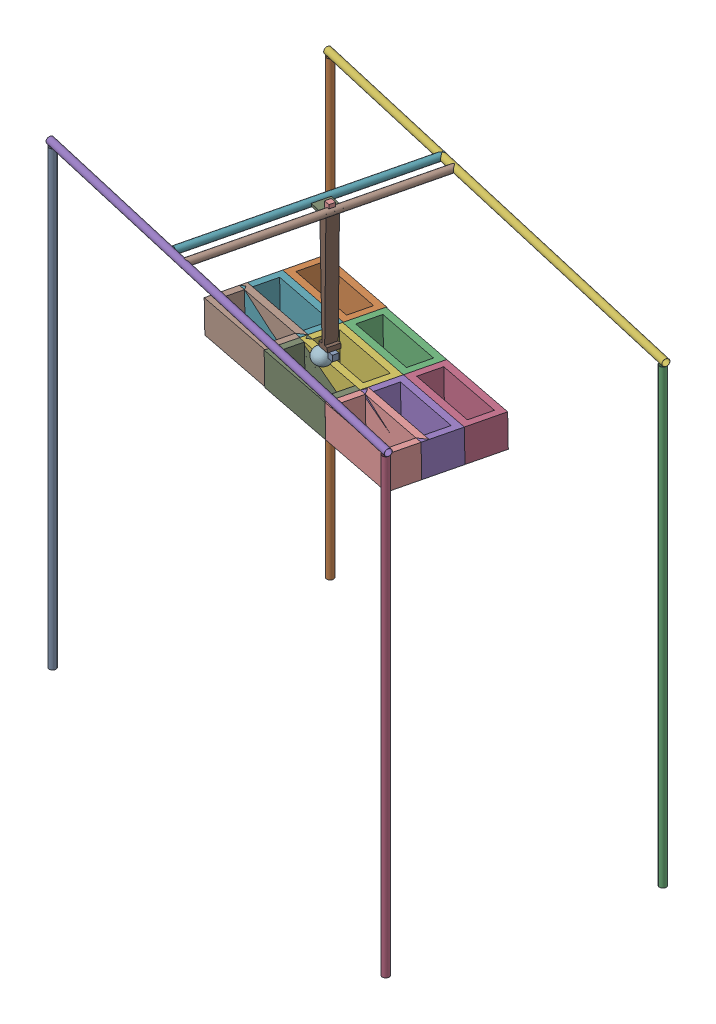
SolidWorks assembly Assem3, configuration Default. Lengths in mm.
Overall size (2218.63 2049.89 1457.96).
22 component instances, 7 part files, 85 mates.
Components (placement in the parent):
- Post-1: Post [Default] at (-708.0978 -578.8244 766.8983) size (30 2000 30)
- Post-2: Post [Default] at (-447.6841 -587.9996 -202.6406) x (-0.685433 0 0.728135) z (-0.728135 0 -0.685433) size (30 2000 30)
- Post-3: Post [Default] at (1471.9629 -588.1508 242.4272) x (0.918656 0 0.395059) z (-0.395059 0 0.918656) size (30 2000 30)
- Post-4: Post [Default] at (1211.4126 -579.3895 1210.0463) x (-0.750465 0 0.660911) z (-0.660911 0 -0.750465) size (30 2000 30)
- Post-5: Post [Default] at (1226.0281 1435.6105 1213.4205) x (-0.214051 -0.307477 0.927168) z (0.069166 -0.951555 -0.299597) size (30 2000 30)
- Post-6: Post [Default] at (1486.9923 1426.4353 244.0087) x (-0.187597 -0.551833 0.812581) z (0.124134 -0.833955 -0.53769) size (30 2000 30)
- CrossBar-1: CrossBar [Default] at (199.2269 1426.3635 -61.3498) x (-0.865673 -0.460846 -0.195528) z (-0.224939 0.009145 0.97433) size (30 30 1000)
- CrossBar-2: CrossBar [Default] at (270.8033 1426.4246 -37.975) x (-0.397766 -0.913702 -0.083254) z (-0.224939 0.009145 0.97433) size (30 30 1000)
- PneumaticBase-1: PneumaticBase [Default] at (100.0341 1426.9597 429.3848) x (0.974371 0 0.224948) z (-0.224939 0.009145 0.97433) size (75 10 75)
- MotorPlaceHolder-1: MotorPlaceHolder [Default] at (144.8147 1436.7365 414.62) x (0.974371 0 0.224948) z (-0.224939 0.009145 0.97433) size (25 25 25)
- PneumaticPlaceHolder-1: PneumaticPlaceHolder [Default] at (173.7901 1021.101 385.5573) x (-0.97362 -0.041413 -0.224386) z (-0.224939 0.009145 0.97433) size (55.74 520 50)
- Scoop-1: Scoop [Default] at (142.921 869.2738 425.0805) x (0.404961 0.888332 0.216502) z (-0.913665 0.402216 0.058646) size (37.5 75 75)
- MotorPlaceHolder-2: MotorPlaceHolder [Default] at (179.0904 883.31 432.6726) x (0.97362 0.041413 0.224386) z (-0.224939 0.009145 0.97433) size (25 25 25)
- Box-1: Box [Default] at (-335.0347 663.8183 117.5582) x (0.97362 0.041413 0.224386) z (-0.224939 0.009145 0.97433) size (360 140 160)
- Box-2: Box [Default] at (14.6565 679.6608 201.6882) x (0.97362 0.041413 0.224386) z (-0.224939 0.009145 0.97433) size (360 140 160)
- Box-3: Box [Default] at (365.1729 694.569 282.41) x (0.97362 0.041413 0.224386) z (-0.224939 0.009145 0.97433) size (360 140 160)
- Box-4: Box [Default] at (329.1827 696.0322 438.3028) x (0.97362 0.041413 0.224386) z (-0.224939 0.009145 0.97433) size (360 140 160)
- Box-5: Box [Default] at (-21.3337 681.124 357.581) x (0.97362 0.041413 0.224386) z (-0.224939 0.009145 0.97433) size (360 140 160)
- Box-6: Box [Default] at (-371.0249 665.2815 273.451) x (0.97362 0.041413 0.224386) z (-0.224939 0.009145 0.97433) size (360 140 160)
- Box-7: Box [Default] at (-400.2669 666.4703 400.1139) x (0.97362 0.041413 0.224386) z (-0.224939 0.009145 0.97433) size (360 140 160)
- Box-8: Box [Default] at (-50.5757 682.3128 484.2439) x (0.97362 0.041413 0.224386) z (-0.224939 0.009145 0.97433) size (360 140 160)
- Box-9: Box [Default] at (299.9407 697.221 564.9657) x (0.97362 0.041413 0.224386) z (-0.224939 0.009145 0.97433) size (360 140 160)
Mates (geometry in assembly coordinates):
- Parallel1: parallel aligned: cylinder of Post-5 through (-722.7133 1435.6105 763.5241) axis (0.974371 0 0.224948) radius 15; cylinder of Post-6 through (-461.7491 1426.4353 -205.8877) axis (0.974371 0 0.224948) radius 15
- Parallel2: parallel aligned: cylinder of Post-1 through (-708.0978 1421.1756 766.8983) axis (0 -1 0) radius 15; cylinder of Post-2 through (-447.6841 1412.0004 -202.6406) axis (0 -1 0) radius 15
- Parallel3: parallel aligned: cylinder of Post-3 through (1471.9629 1411.8492 242.4272) axis (0 -1 0) radius 15; cylinder of Post-4 through (1211.4126 1420.6105 1210.0463) axis (0 -1 0) radius 15
- Parallel4: parallel aligned: cylinder of Post-1 through (-708.0978 1421.1756 766.8983) axis (0 -1 0) radius 15; cylinder of Post-4 through (1211.4126 1420.6105 1210.0463) axis (0 -1 0) radius 15
- Parallel5: parallel aligned: cylinder of Post-3 through (1471.9629 1411.8492 242.4272) axis (0 -1 0) radius 15; cylinder of Post-4 through (1211.4126 1420.6105 1210.0463) axis (0 -1 0) radius 15
- Parallel6: parallel aligned: cylinder of Post-2 through (-447.6841 1412.0004 -202.6406) axis (0 -1 0) radius 15; cylinder of Post-3 through (1471.9629 1411.8492 242.4272) axis (0 -1 0) radius 15
- Perpendicular1: perpendicular: cylinder of Post-2 through (-447.6841 1412.0004 -202.6406) axis (0 -1 0) radius 15; cylinder of Post-6 through (-461.7491 1426.4353 -205.8877) axis (0.974371 0 0.224948) radius 15
- Perpendicular2: perpendicular: cylinder of Post-2 through (-447.6841 1412.0004 -202.6406) axis (0 -1 0) radius 15; cylinder of Post-5 through (-722.7133 1435.6105 763.5241) axis (0.974371 0 0.224948) radius 15
- Perpendicular8: perpendicular: cylinder of Post-4 through (1211.4126 1420.6105 1210.0463) axis (0 -1 0) radius 15; cylinder of Post-5 through (-722.7133 1435.6105 763.5241) axis (0.974371 0 0.224948) radius 15
- Perpendicular9: perpendicular: cylinder of Post-1 through (-708.0978 1421.1756 766.8983) axis (0 -1 0) radius 15; cylinder of Post-5 through (-722.7133 1435.6105 763.5241) axis (0.974371 0 0.224948) radius 15
- Perpendicular10: perpendicular: cylinder of Post-3 through (1471.9629 1411.8492 242.4272) axis (0 -1 0) radius 15; cylinder of Post-6 through (-461.7491 1426.4353 -205.8877) axis (0.974371 0 0.224948) radius 15
- Perpendicular11: perpendicular: cylinder of Post-2 through (-447.6841 1412.0004 -202.6406) axis (0 -1 0) radius 15; cylinder of Post-6 through (-461.7491 1426.4353 -205.8877) axis (0.974371 0 0.224948) radius 15
- Perpendicular17: perpendicular: cylinder of Post-1 through (-708.0978 1421.1756 766.8983) axis (0 -1 0) radius 15; cylinder of Post-5 through (-722.7133 1435.6105 763.5241) axis (0.974371 0 0.224948) radius 15
- Perpendicular18: perpendicular: cylinder of Post-4 through (1211.4126 1420.6105 1210.0463) axis (0 -1 0) radius 15; cylinder of Post-5 through (-722.7133 1435.6105 763.5241) axis (0.974371 0 0.224948) radius 15
- Tangent23: tangent: circle of Post-1; circle of Post-5
- Tangent24: tangent: circle of Post-4; circle of Post-5
- Tangent29: tangent: circle of Post-2; circle of Post-6
- Tangent32: tangent: plane of Post-3; plane of Post-6 through (1486.9923 1426.4353 244.0087) normal (0.974371 0 0.224948)
- Lock1: lock: unknown of Post-3; unknown of Post-6
- Lock2: lock: unknown of Post-2; unknown of Post-6
- Lock3: lock: unknown of Post-1; unknown of Post-5
- Lock4: lock: unknown of Post-4; unknown of Post-5
- Perpendicular21: perpendicular: cylinder of Post-5 through (-722.7133 1435.6105 763.5241) axis (0.974371 0 0.224948) radius 15; cylinder of CrossBar-1 through (-25.7119 1435.5085 912.9802) axis (0.224939 -0.009145 -0.97433) radius 15
- Tangent38: tangent aligned: cylinder of Post-6 through (-461.7491 1426.4353 -205.8877) axis (0.974371 0 0.224948) radius 15; cylinder of CrossBar-1 through (-25.7119 1435.5085 912.9802) axis (0.224939 -0.009145 -0.97433) radius 15
- Tangent40: tangent aligned: cylinder of Post-5 through (-722.7133 1435.6105 763.5241) axis (0.974371 0 0.224948) radius 15; cylinder of CrossBar-2 through (45.8645 1435.5695 936.355) axis (0.224939 -0.009145 -0.97433) radius 15
- Distance4: distance = 75 mm: cylinder of CrossBar-1 through (-25.7119 1435.5085 912.9802) axis (0.224939 -0.009145 -0.97433) radius 15; cylinder of CrossBar-2 through (45.8645 1435.5695 936.355) axis (0.224939 -0.009145 -0.97433) radius 15
- Lock7: lock: unknown of Post-3; unknown of Post-4
- Lock8: lock: unknown of Post-1; unknown of Post-2
- Coincident14: coincident: cylinder of CrossBar-2 through (45.8645 1435.5695 936.355) axis (0.224939 -0.009145 -0.97433) radius 15; line of PneumaticBase-1 through (173.1324 1436.9593 446.1668) axis (0.224939 -0.009145 -0.97433)
- Coincident16: coincident: cylinder of CrossBar-1 through (-25.7119 1435.5085 912.9802) axis (0.224939 -0.009145 -0.97433) radius 15; line of PneumaticBase-1 through (116.925 1436.2734 356.2209) axis (-0.224939 0.009145 0.97433)
- Parallel23: parallel aligned: cylinder of Post-5 through (-722.7133 1435.6105 763.5241) axis (0.974371 0 0.224948) radius 15; line of PneumaticBase-1 through (100.0546 1436.9593 429.2957) axis (0.974371 0 0.224948)
- Parallel24: parallel anti-aligned: cylinder of Post-6 through (-461.7491 1426.4353 -205.8877) axis (0.974371 0 0.224948) radius 15; line of PneumaticBase-1 through (190.0028 1436.2734 373.0921) axis (-0.974371 0 -0.224948)
- Tangent47: tangent: cylinder of CrossBar-1 through (-25.7119 1435.5085 912.9802) axis (0.224939 -0.009145 -0.97433) radius 15; line of PneumaticBase-1 through (116.925 1436.2734 356.2209) axis (-0.224939 0.009145 0.97433)
- Tangent48: tangent: cylinder of CrossBar-2 through (45.8645 1435.5695 936.355) axis (0.224939 -0.009145 -0.97433) radius 15; line of PneumaticBase-1 through (173.1324 1436.9593 446.1668) axis (0.224939 -0.009145 -0.97433)
- Coincident24: coincident anti-aligned: plane of PneumaticBase-1 through (100.0546 1436.9593 429.2957) normal (0.002057 0.999958 -0.008911); plane of MotorPlaceHolder-1 through (144.8147 1436.7365 414.62) normal (-0.002057 -0.999958 0.008911)
- Parallel25: parallel aligned: plane of PneumaticBase-1 through (116.925 1436.2734 356.2209) normal (0.224939 -0.009145 -0.97433); plane of MotorPlaceHolder-1 through (150.4896 1461.5068 390.039) normal (0.224939 -0.009145 -0.97433)
- Lock10: lock: unknown of PneumaticBase-1; unknown of MotorPlaceHolder-1
- Coincident27: coincident anti-aligned: plane of PneumaticBase-1 through (100.0341 1426.9597 429.3848) normal (-0.002057 -0.999958 0.008911); plane of PneumaticPlaceHolder-1 through (163.3769 1426.8408 430.6623) normal (0.002057 0.999958 -0.008911)
- Parallel27: parallel aligned: plane of PneumaticBase-1 through (100.0546 1436.9593 429.2957) normal (-0.224939 0.009145 0.97433); plane of PneumaticPlaceHolder-1 through (162.5431 1021.5583 434.2738) normal (-0.224939 0.009145 0.97433)
- Parallel28: parallel anti-aligned: plane of MotorPlaceHolder-1 through (144.8661 1461.7354 414.3972) normal (-0.974371 0 -0.224948); plane of PneumaticPlaceHolder-1 through (167.0907 1021.5583 435.3237) normal (0.974371 0 0.224948)
- Lock11: lock: unknown of PneumaticBase-1; unknown of PneumaticPlaceHolder-1
- Coincident33: coincident anti-aligned: plane of PneumaticPlaceHolder-1 through (166.8987 907.9322 436.3458) normal (0.038298 -0.9991 0.018219); plane of MotorPlaceHolder-2 through (178.1329 908.2875 432.2171) normal (-0.038298 0.9991 -0.018219)
- Parallel31: parallel aligned: plane of PneumaticPlaceHolder-1 through (162.5431 1021.5583 434.2738) normal (-0.224939 0.009145 0.97433); plane of MotorPlaceHolder-2 through (178.1329 908.2875 432.2171) normal (-0.224939 0.009145 0.97433)
- Parallel32: parallel aligned: plane of PneumaticPlaceHolder-1 through (129.1518 1020.1379 426.5782) normal (-0.97362 -0.041413 -0.224386); plane of MotorPlaceHolder-2 through (178.1329 908.2875 432.2171) normal (-0.97362 -0.041413 -0.224386)
- Tangent51: tangent anti-aligned: sphere of Scoop-1; plane of MotorPlaceHolder-2 through (178.1329 908.2875 432.2171) normal (-0.97362 -0.041413 -0.224386)
- Lock12: lock: unknown of PneumaticPlaceHolder-1; unknown of MotorPlaceHolder-2
- Tangent52: tangent anti-aligned: plane of PneumaticPlaceHolder-1 through (166.8987 907.9322 436.3458) normal (0.038298 -0.9991 0.018219); sphere of Scoop-1
- Tangent53: tangent anti-aligned: sphere of Scoop-1; plane of MotorPlaceHolder-2 through (178.1329 908.2875 432.2171) normal (-0.97362 -0.041413 -0.224386)
- Coincident34: coincident anti-aligned: plane of Box-1 through (10.1068 818.6011 195.7866) normal (0.97362 0.041413 0.224386); plane of Box-2 through (9.2948 819.5348 199.1375) normal (-0.97362 -0.041413 -0.224386)
- Coincident35: coincident anti-aligned: plane of Box-2 through (359.798 834.4436 279.9165) normal (0.97362 0.041413 0.224386); plane of Box-3 through (359.8112 834.443 279.8593) normal (-0.97362 -0.041413 -0.224386)
- Parallel33: parallel aligned: plane of Box-2 through (9.2948 819.5348 199.1375) normal (-0.224939 0.009145 0.97433); plane of Box-3 through (359.8112 834.443 279.8593) normal (-0.224939 0.009145 0.97433)
- Parallel34: parallel aligned: plane of Box-1 through (-340.3964 803.6923 115.0075) normal (-0.224939 0.009145 0.97433); plane of Box-2 through (9.2948 819.5348 199.1375) normal (-0.224939 0.009145 0.97433)
- Parallel35: parallel aligned: plane of Box-2 through (45.285 818.0716 43.2447) normal (0.224939 -0.009145 -0.97433); plane of Box-3 through (395.8014 832.9798 123.9665) normal (0.224939 -0.009145 -0.97433)
- Parallel36: parallel aligned: plane of Box-1 through (-304.4062 802.2291 -40.8853) normal (0.224939 -0.009145 -0.97433); plane of Box-2 through (45.285 818.0716 43.2447) normal (0.224939 -0.009145 -0.97433)
- Parallel37: parallel aligned: plane of Box-1 through (-335.0347 663.8183 117.5582) normal (0.038298 -0.9991 0.018219); plane of Box-2 through (14.6565 679.6608 201.6882) normal (0.038298 -0.9991 0.018219)
- Coincident41: coincident aligned: plane of Box-2 through (14.6565 679.6608 201.6882) normal (0.038298 -0.9991 0.018219); plane of Box-3 through (365.1729 694.569 282.41) normal (0.038298 -0.9991 0.018219)
- Lock13: lock: unknown of Box-1; unknown of Box-2
- Lock14: lock: unknown of Box-2; unknown of Box-3
- Parallel38: parallel aligned: plane of PneumaticPlaceHolder-1 through (147.8851 1020.9348 430.8956) normal (-0.97362 -0.041413 -0.224386); plane of Box-1 through (-340.3964 803.6923 115.0075) normal (-0.97362 -0.041413 -0.224386)
- Parallel39: parallel aligned: plane of MotorPlaceHolder-1 through (144.8661 1461.7354 414.3972) normal (-0.224939 0.009145 0.97433); plane of Box-2 through (9.2948 819.5348 199.1375) normal (-0.224939 0.009145 0.97433)
- Parallel40: parallel aligned: plane of MotorPlaceHolder-2 through (202.4734 909.3228 437.8267) normal (0.97362 0.041413 0.224386); plane of Box-3 through (710.3144 849.3518 360.6383) normal (0.97362 0.041413 0.224386)
- Coincident47: coincident aligned: plane of Box-4 through (329.1827 696.0322 438.3028) normal (0.038298 -0.9991 0.018219); plane of Box-5 through (-21.3337 681.124 357.581) normal (0.038298 -0.9991 0.018219)
- Parallel41: parallel aligned: plane of Box-5 through (-21.3337 681.124 357.581) normal (0.038298 -0.9991 0.018219); plane of Box-6 through (-371.0249 665.2815 273.451) normal (0.038298 -0.9991 0.018219)
- Lock15: lock: unknown of Box-5; unknown of Box-6
- Lock16: lock: unknown of Box-4; unknown of Box-5
- Parallel42: parallel aligned: plane of Box-5 through (-26.6954 820.998 355.0303) normal (-0.224939 0.009145 0.97433); plane of Box-6 through (-376.3866 805.1555 270.9003) normal (-0.224939 0.009145 0.97433)
- Coincident48: coincident anti-aligned: plane of Box-5 through (-26.6954 820.998 355.0303) normal (-0.97362 -0.041413 -0.224386); plane of Box-6 through (-25.8834 820.0643 351.6793) normal (0.97362 0.041413 0.224386)
- Parallel43: parallel aligned: plane of Box-4 through (359.8112 834.443 279.8593) normal (0.224939 -0.009145 -0.97433); plane of Box-5 through (9.2948 819.5348 199.1375) normal (0.224939 -0.009145 -0.97433)
- Parallel44: parallel aligned: plane of Box-5 through (9.2948 819.5348 199.1375) normal (0.224939 -0.009145 -0.97433); plane of Box-6 through (-340.3964 803.6923 115.0075) normal (0.224939 -0.009145 -0.97433)
- Parallel45: parallel aligned: plane of Box-4 through (323.821 835.9062 435.7521) normal (-0.224939 0.009145 0.97433); plane of Box-5 through (-26.6954 820.998 355.0303) normal (-0.224939 0.009145 0.97433)
- Coincident49: coincident anti-aligned: plane of Box-4 through (323.821 835.9062 435.7521) normal (-0.97362 -0.041413 -0.224386); plane of Box-5 through (323.8078 835.9068 435.8093) normal (0.97362 0.041413 0.224386)
- Coincident51: coincident anti-aligned: line of Box-2 through (9.2948 819.5348 199.1375) axis (0.97362 0.041413 0.224386); line of Box-5 through (359.798 834.4436 279.9165) axis (-0.97362 -0.041413 -0.224386)
- Coincident52: coincident aligned: line of Box-3 through (710.3144 849.3518 360.6383) axis (0.224939 -0.009145 -0.97433); line of Box-4 through (674.3242 850.815 516.5311) axis (0.224939 -0.009145 -0.97433)
- Parallel46: parallel aligned: plane of Box-7 through (-400.2669 666.4703 400.1139) normal (0.038298 -0.9991 0.018219); plane of Box-8 through (-50.5757 682.3128 484.2439) normal (0.038298 -0.9991 0.018219)
- Coincident53: coincident anti-aligned: plane of Box-7 through (-55.1255 821.2531 478.3422) normal (0.97362 0.041413 0.224386); plane of Box-8 through (-55.9375 822.1869 481.6932) normal (-0.97362 -0.041413 -0.224386)
- Parallel47: parallel aligned: plane of Box-8 through (-19.9473 820.7237 325.8004) normal (0.224939 -0.009145 -0.97433); plane of Box-9 through (330.5691 835.6319 406.5222) normal (0.224939 -0.009145 -0.97433)
- Parallel48: parallel aligned: plane of Box-7 through (-405.6286 806.3444 397.5632) normal (-0.224939 0.009145 0.97433); plane of Box-8 through (-55.9375 822.1869 481.6932) normal (-0.224939 0.009145 0.97433)
- Lock17: lock: unknown of Box-7; unknown of Box-8
- Lock18: lock: unknown of Box-8; unknown of Box-9
- Parallel49: parallel aligned: plane of Box-8 through (-55.9375 822.1869 481.6932) normal (-0.224939 0.009145 0.97433); plane of Box-9 through (294.5789 837.0951 562.415) normal (-0.224939 0.009145 0.97433)
- Coincident54: coincident anti-aligned: plane of Box-8 through (294.5657 837.0956 562.4722) normal (0.97362 0.041413 0.224386); plane of Box-9 through (294.5789 837.0951 562.415) normal (-0.97362 -0.041413 -0.224386)
- Parallel50: parallel aligned: plane of Box-7 through (-369.6384 804.8812 241.6704) normal (0.224939 -0.009145 -0.97433); plane of Box-8 through (-19.9473 820.7237 325.8004) normal (0.224939 -0.009145 -0.97433)
- Coincident55: coincident aligned: plane of Box-8 through (-50.5757 682.3128 484.2439) normal (0.038298 -0.9991 0.018219); plane of Box-9 through (299.9407 697.221 564.9657) normal (0.038298 -0.9991 0.018219)
- Coincident56: coincident: line of Box-4 through (674.3242 850.815 516.5311) axis (0.224939 -0.009145 -0.97433); plane of Box-9 through (645.0821 852.0038 643.194) normal (0.97362 0.041413 0.224386)
- Coincident57: coincident anti-aligned: line of Box-5 through (9.2613 821.9661 332.532) axis (0.97362 0.041413 0.224386); line of Box-8 through (330.5559 835.6324 406.5794) axis (-0.97362 -0.041413 -0.224386)
